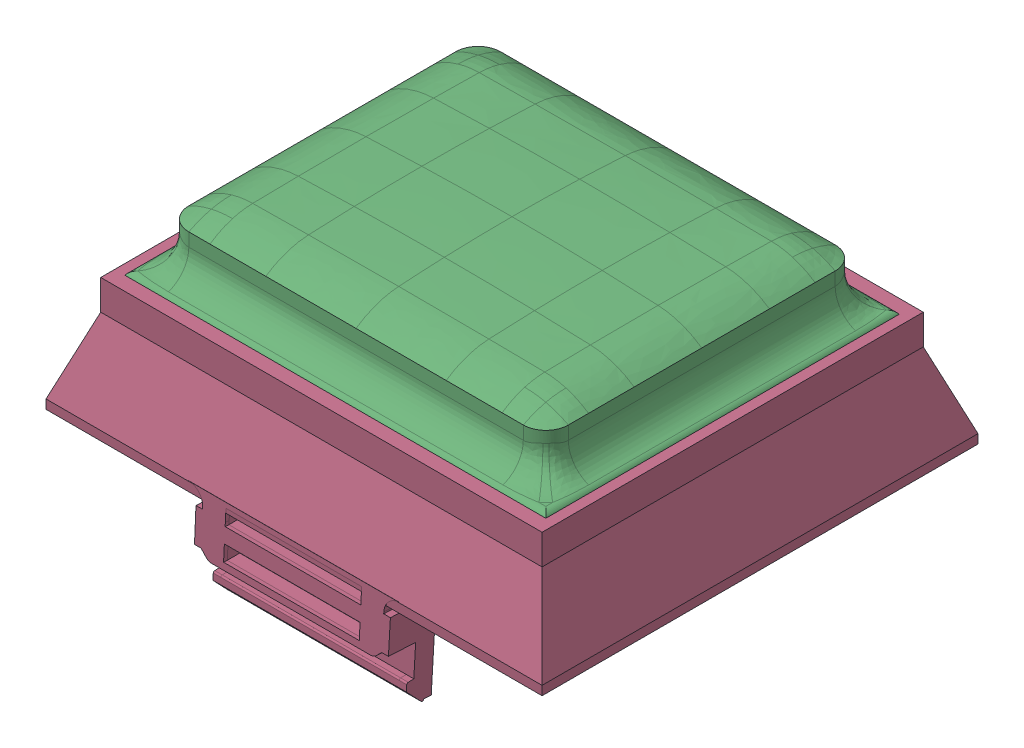
SolidWorks assembly Conti, configuration 默认. Lengths in mm.
Overall size (33 18.27 29.5).
5 component instances, 5 part files, 13 mates.
Components (placement in the parent):
- Contilensall-1: Contilensall [默认] at origin size (28.33 2.18 23.83)
- InsideSkin_conti-1: InsideSkin_conti [默认] at (0.0001 0 0.2499) size (23.8 5.48 19.29)
- ContiTopskin-1: ContiTopskin [默认] at (0.0001 2 0.2499) size (28.02 6.25 23.52)
- ContiSupportBase-2: ContiSupportBase [默认] at origin size (33 14.02 29.5)
- continuous-1: continuous [默认] at (-10.2499 23.3 7.7499) x (1 0 0) z (0 1 0) size (22 16 0.4)
Mates (geometry in assembly coordinates):
- 同心2: concentric anti-aligned: cylinder of InsideSkin_conti-1 through (10.8751 17.7531 8.6249) axis (0 1 0) radius 0.7; cylinder of Board3Con1612611OriginalSkin_TOP-1 through (10.8751 24 8.6249) axis (0 -1 0) radius 0.7
- 同心3: concentric anti-aligned: cylinder of InsideSkin_conti-1 through (10.8751 17.7531 -9.1251) axis (0 1 0) radius 0.7; cylinder of Board3Con1612611OriginalSkin_TOP-1 through (10.8751 24 -9.1251) axis (0 -1 0) radius 0.7
- 重合4: coincident aligned: plane of InsideSkin_conti-1 through (10.8751 19 -9.1251) normal (0 -1 0); plane of Board3Con1612611OriginalSkin_TOP-1 through (0.0001 19 0.2499) normal (0 -1 0)
- 重合6: coordinate: point of ContiSupportBase-2
- 重合7: coincident anti-aligned: plane of lensall-1 through (13.75 19 -11.5) normal (0.939693 0.34202 0); plane of ContiSupportBase-2 through (13.75 19 12.7803) normal (-0.939693 -0.34202 0)
- 同心5: concentric aligned: cylinder of lensall-1 through (13.3294 18.6938 -11.0794) axis (-0.323616 0.889126 0.323616) radius 0.5; cylinder of ContiSupportBase-2 through (10.7866 25.6801 -8.5366) axis (-0.323616 0.889126 0.323616) radius 0.5
- 重合8: coincident anti-aligned: plane of lensall-1 through (0 18 0) normal (0 -1 0); plane of ContiSupportBase-2 through (0 18 0) normal (0 1 0)
- 重合9: coincident anti-aligned: plane of lensall-1 through (0 19 0) normal (0 1 0); plane of Board3Con1612611OriginalSkin_TOP-1 through (0.0001 19 0.2499) normal (0 -1 0)
- 重合10: coincident anti-aligned: plane of Board3Con1612611OriginalSkin_TOP-1 through (0.0001 19 11.7499) normal (0 0 1); plane of ContiSupportBase-2 through (-13.5999 21 11.7499) normal (0 0 -1)
- 重合11: coincident anti-aligned: plane of Board3Con1612611OriginalSkin_TOP-1 through (14.0001 19 0.2499) normal (1 0 0); plane of ContiSupportBase-2 through (14.0001 21 11.7499) normal (-1 0 0)
- 宽度1: width: plane of InsideSkin_conti-1 through (-11.3749 17.7531 -9.8251) normal (0 0 -1); plane of InsideSkin_conti-1 through (-11.3749 17.7531 9.3249) normal (0 0 1); plane of continuous-1 through (-11.2499 33.7392 -8.2501) normal (0 0 -1); plane of continuous-1 through (-10.2499 34.1392 7.7499) normal (0 0 1)
- 宽度2: width: plane of continuous-1 through (-11.2499 33.7392 -3.2352) normal (-1 0 0); plane of continuous-1 through (10.7501 34.1392 7.7499) normal (1 0 0); plane of InsideSkin_conti-1 through (-12.0749 17.7531 -9.1251) normal (-1 0 0); plane of InsideSkin_conti-1 through (11.5751 17.7531 -9.1251) normal (1 0 0)
- 重合12: coincident aligned: line of InsideSkin_conti-1 through (-10.2499 23.7 -5.2501) axis (0 0 -1); line of continuous-1 through (-10.2499 34.1392 -5.2501) axis (0 0 -1)
